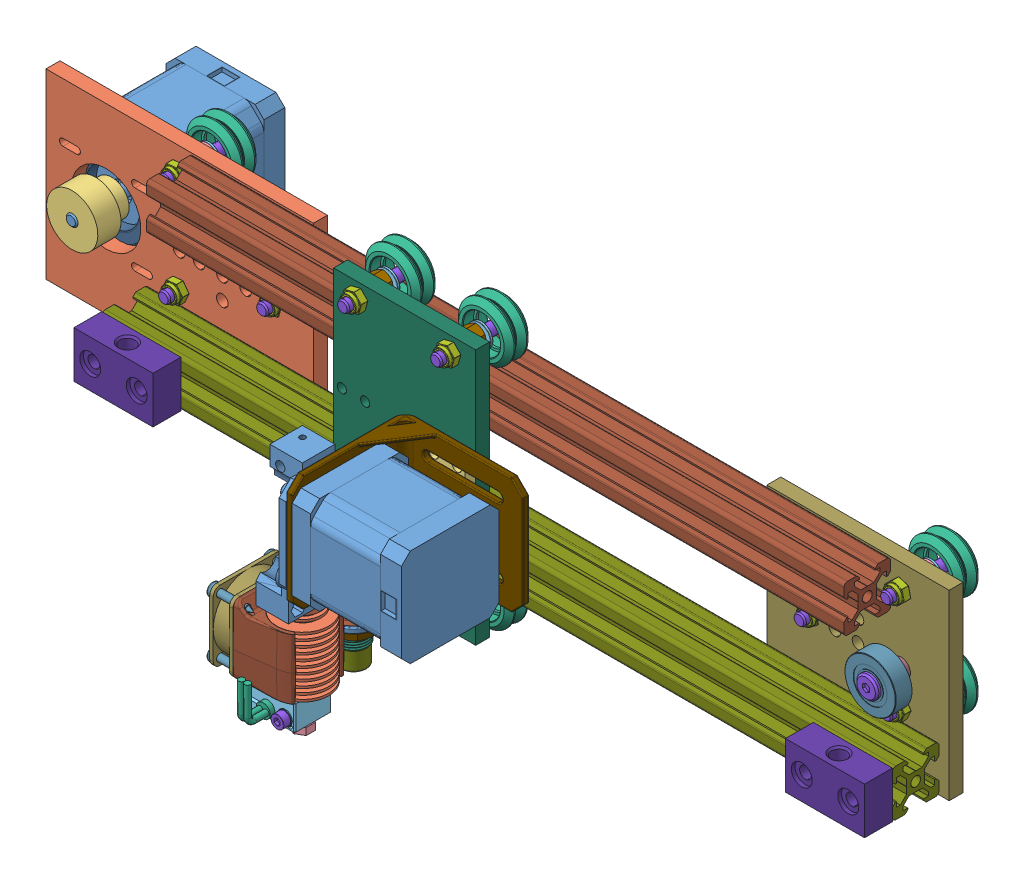
SolidWorks assembly X Axis, configuration Default. Lengths in mm.
107 component instances, 39 part files, 51 mates.
Components (placement in the parent):
- X Motor-1: X Motor [Default] at (-35.3266 39.1515 56.2965) size (149.33 96.33 71)
  - NEMA17_48-1: NEMA17_48 [Default] at (18.5315 36.8987 58.8087) size (42 42 71)
  - X Stepper Mount-1: X Stepper Mount [Default] at (71.5315 36.8987 64.7087) x (1 0 0) z (0 -1 0) size (115 6 78.4)
  - GT2 Pulley-1: GT2 Pulley [Default] at (18.5315 36.8987 72.2337) x (0.991394 0.130915 0) z (-0.130915 0.991394 0) size (22 17 22)
  - Delrin Assembly-1: Delrin Assembly [Default] at (52.9627 66.0979 58.7087) x (0 0 1) z (0.923728 0.383049 0) size (31.75 33.75 33.75)
    - Aluminum Spacer-1: Aluminum Spacer [6mm] at origin size (6 10 10)
    - Precision Shim 10x5x1mm-1: Precision Shim 10x5x1mm [Default] at (-1 0 0) x (1 0 0) z (0 0.993706 0.112022) size (1 10 10)
    - Dual V-Wheel Delrin-1: Dual V-Wheel Delrin [Default] at (-6.115 0 0) x (0 -0.740375 0.672194) z (-1 0 0) size (23.89 23.89 10.23)
    - Nylon Insert Hex Locknut M5-1: Nylon Insert Hex Locknut M5 [Default] at (12 0 0) x (0 -0.231787 0.972767) z (1 0 0) size (7.68 8.82 4.5)
    - 5mm Low Profile Socket Head Screw-1: 5mm Low Profile Socket Head Screw [5mm x 30mm Low Profile Screw] at (-12.98 0 0) x (1 0 0) z (0 0.597414 0.801933) size (31.75 9.5 9.5)
  - Delrin Assembly-2: Delrin Assembly [Default] at (52.9627 22.6994 58.7087) x (0 0 1) z (0.923728 0.383049 0) size (31.75 33.75 33.75)
    - Aluminum Spacer-1: Aluminum Spacer [6mm] at origin size (6 10 10)
    - Precision Shim 10x5x1mm-1: Precision Shim 10x5x1mm [Default] at (-1 0 0) x (1 0 0) z (0 0.993706 0.112022) size (1 10 10)
    - Dual V-Wheel Delrin-1: Dual V-Wheel Delrin [Default] at (-6.115 0 0) x (0 -0.740375 0.672194) z (-1 0 0) size (23.89 23.89 10.23)
    - Nylon Insert Hex Locknut M5-1: Nylon Insert Hex Locknut M5 [Default] at (12 0 0) x (0 -0.231787 0.972767) z (1 0 0) size (7.68 8.82 4.5)
    - 5mm Low Profile Socket Head Screw-1: 5mm Low Profile Socket Head Screw [5mm x 30mm Low Profile Screw] at (-12.98 0 0) x (1 0 0) z (0 0.597414 0.801933) size (31.75 9.5 9.5)
  - Eccentric Delrin Assembly-1: Eccentric Delrin Assembly [Default] at (91.8727 36.8987 61.2087) x (0 0 -1) z (1 0 0) size (31.75 27.59 27.59)
    - Steel Eccentric Spacer-1: Steel Eccentric Spacer [6mm - Mini] at origin size (8.5 9.09 8.71)
    - Precision Shim 10x5x1mm-1: Precision Shim 10x5x1mm [Default] at (6 0 0.79) x (-1 0 0) z (0 0.812589 -0.582837) size (1 10 10)
    - Nylon Insert Hex Locknut M5-1: Nylon Insert Hex Locknut M5 [Default] at (-7 0 0.79) x (0 -0.700969 -0.713192) z (-1 0 0) size (7.68 8.82 4.5)
    - Dual V-Wheel Delrin-1: Dual V-Wheel Delrin [Default] at (11.115 0 0.79) x (0 0.169483 -0.985533) z (1 0 0) size (23.89 23.89 10.23)
    - 5mm Low Profile Socket Head Screw-1: 5mm Low Profile Socket Head Screw [5mm x 30mm Low Profile Screw] at (17.98 0 0.79) x (-1 0 0) z (0 -0.935654 -0.352919) size (31.75 9.5 9.5)
  - Stepper Damper-1: Stepper Damper [Default] at (18.5317 36.8985 58.8087) x (0.707107 0.707107 0) z (0.707107 -0.707107 0) size (51.85 6.11 80.79)
- Upper X Rail-1: Upper X Rail [Default] at (23.5992 105.2494 137.0052) x (0 0 1) z (1 0 0) size (20 20 300)
- X End-1: X End [Default] at (349.9804 66.2549 121.0052) x (-1 0 0) z (0 1 0) size (78.4 6 78.4)
- Delrin Assembly-1: Delrin Assembly [Default] at (328.1737 61.8509 115.0052) x (0 0 1) z (-0.14439 -0.989521 0) size (31.75 33.75 33.75)
  - Aluminum Spacer-1: Aluminum Spacer [6mm] at origin size (6 10 10)
  - Precision Shim 10x5x1mm-1: Precision Shim 10x5x1mm [Default] at (-1 0 0) x (1 0 0) z (0 0.993706 0.112022) size (1 10 10)
  - Dual V-Wheel Delrin-1: Dual V-Wheel Delrin [Default] at (-6.115 0 0) x (0 -0.740375 0.672194) z (-1 0 0) size (23.89 23.89 10.23)
  - Nylon Insert Hex Locknut M5-1: Nylon Insert Hex Locknut M5 [Default] at (12 0 0) x (0 -0.231787 0.972767) z (1 0 0) size (7.68 8.82 4.5)
  - 5mm Low Profile Socket Head Screw-1: 5mm Low Profile Socket Head Screw [5mm x 30mm Low Profile Screw] at (-12.98 0 0) x (1 0 0) z (0 0.597414 0.801933) size (31.75 9.5 9.5)
- Delrin Assembly-2: Delrin Assembly [Default] at (328.1737 105.2494 115.0052) x (0 0 1) z (-1 0 0) size (31.75 33.75 33.75)
  - Aluminum Spacer-1: Aluminum Spacer [6mm] at origin size (6 10 10)
  - Precision Shim 10x5x1mm-1: Precision Shim 10x5x1mm [Default] at (-1 0 0) x (1 0 0) z (0 0.993706 0.112022) size (1 10 10)
  - Dual V-Wheel Delrin-1: Dual V-Wheel Delrin [Default] at (-6.115 0 0) x (0 -0.740375 0.672194) z (-1 0 0) size (23.89 23.89 10.23)
  - Nylon Insert Hex Locknut M5-1: Nylon Insert Hex Locknut M5 [Default] at (12 0 0) x (0 -0.231787 0.972767) z (1 0 0) size (7.68 8.82 4.5)
  - 5mm Low Profile Socket Head Screw-1: 5mm Low Profile Socket Head Screw [5mm x 30mm Low Profile Screw] at (-12.98 0 0) x (1 0 0) z (0 0.597414 0.801933) size (31.75 9.5 9.5)
- Eccentric Delrin Assembly-1: Eccentric Delrin Assembly [Default] at (289.2035 76.3528 117.5052) x (0 0 -1) z (-0.923728 -0.383049 0) size (31.75 27.59 27.59)
  - Steel Eccentric Spacer-1: Steel Eccentric Spacer [6mm - Mini] at origin size (8.5 9.09 8.71)
  - Precision Shim 10x5x1mm-1: Precision Shim 10x5x1mm [Default] at (6 0 0.79) x (-1 0 0) z (0 0.812589 -0.582837) size (1 10 10)
  - Nylon Insert Hex Locknut M5-1: Nylon Insert Hex Locknut M5 [Default] at (-7 0 0.79) x (0 -0.700969 -0.713192) z (-1 0 0) size (7.68 8.82 4.5)
  - Dual V-Wheel Delrin-1: Dual V-Wheel Delrin [Default] at (11.115 0 0.79) x (0 0.169483 -0.985533) z (1 0 0) size (23.89 23.89 10.23)
  - 5mm Low Profile Socket Head Screw-1: 5mm Low Profile Socket Head Screw [5mm x 30mm Low Profile Screw] at (17.98 0 0.79) x (-1 0 0) z (0 -0.935654 -0.352919) size (31.75 9.5 9.5)
- 5mm Low Profile Socket Head Screw-1: 5mm Low Profile Socket Head Screw [5mm x 30mm Low Profile Screw] at (328.1737 76.0502 142.1052) x (0 0 -1) z (1 0 0) size (31.75 9.5 9.5)
- Nylon Spacer-1: Nylon Spacer [.25 inch] at (328.1737 76.0502 133.3552) x (0 0 -1) z (1 0 0) size (6.35 7.94 7.94)
- Ball Bearing 608Z-1: Ball Bearing 608Z [Default] at (328.1737 76.0502 136.8552) x (0 0 -1) z (1 0 0) size (7 22 22)
- Nylon Insert Hex Locknut M5-1: Nylon Insert Hex Locknut M5 [Default] at (328.1737 76.0502 121.0052) x (-0.923728 -0.383049 0) z (0 0 -1) size (7.68 8.82 4.5)
- X Carriage-1: X Carriage [Default] at (142.7674 76.0502 149.1202) x (1 0 0) z (0 -1 0) size (61.08 6 110.03)
- Eccentric Delrin Assembly-2: Eccentric Delrin Assembly [Default] at (161.9774 125.1002 148.1202) x (0 0 -1) z (1 0 0) size (31.75 27.59 27.59)
  - Steel Eccentric Spacer-1: Steel Eccentric Spacer [6mm - Mini] at origin size (8.5 9.09 8.71)
  - Precision Shim 10x5x1mm-1: Precision Shim 10x5x1mm [Default] at (6 0 0.79) x (-1 0 0) z (0 0.812589 -0.582837) size (1 10 10)
  - Nylon Insert Hex Locknut M5-1: Nylon Insert Hex Locknut M5 [Default] at (-7 0 0.79) x (0 -0.700969 -0.713192) z (-1 0 0) size (7.68 8.82 4.5)
  - Dual V-Wheel Delrin-1: Dual V-Wheel Delrin [Default] at (11.115 0 0.79) x (0 0.169483 -0.985533) z (1 0 0) size (23.89 23.89 10.23)
  - 5mm Low Profile Socket Head Screw-1: 5mm Low Profile Socket Head Screw [5mm x 30mm Low Profile Screw] at (17.98 0 0.79) x (-1 0 0) z (0 -0.935654 -0.352919) size (31.75 9.5 9.5)
- Delrin Assembly-3: Delrin Assembly [Default] at (122.7674 27.0002 143.1202) x (0 0 1) z (-1 0 0) size (31.75 33.75 33.75)
  - Aluminum Spacer-1: Aluminum Spacer [6mm] at origin size (6 10 10)
  - Precision Shim 10x5x1mm-1: Precision Shim 10x5x1mm [Default] at (-1 0 0) x (1 0 0) z (0 0.993706 0.112022) size (1 10 10)
  - Dual V-Wheel Delrin-1: Dual V-Wheel Delrin [Default] at (-6.115 0 0) x (0 -0.740375 0.672194) z (-1 0 0) size (23.89 23.89 10.23)
  - Nylon Insert Hex Locknut M5-1: Nylon Insert Hex Locknut M5 [Default] at (12 0 0) x (0 -0.231787 0.972767) z (1 0 0) size (7.68 8.82 4.5)
  - 5mm Low Profile Socket Head Screw-1: 5mm Low Profile Socket Head Screw [5mm x 30mm Low Profile Screw] at (-12.98 0 0) x (1 0 0) z (0 0.597414 0.801933) size (31.75 9.5 9.5)
- Delrin Assembly-4: Delrin Assembly [Default] at (162.7674 27.0002 143.1202) x (0 0 1) z (-1 0 0) size (31.75 33.75 33.75)
  - Aluminum Spacer-1: Aluminum Spacer [6mm] at origin size (6 10 10)
  - Precision Shim 10x5x1mm-1: Precision Shim 10x5x1mm [Default] at (-1 0 0) x (1 0 0) z (0 0.993706 0.112022) size (1 10 10)
  - Dual V-Wheel Delrin-1: Dual V-Wheel Delrin [Default] at (-6.115 0 0) x (0 -0.740375 0.672194) z (-1 0 0) size (23.89 23.89 10.23)
  - Nylon Insert Hex Locknut M5-1: Nylon Insert Hex Locknut M5 [Default] at (12 0 0) x (0 -0.231787 0.972767) z (1 0 0) size (7.68 8.82 4.5)
  - 5mm Low Profile Socket Head Screw-1: 5mm Low Profile Socket Head Screw [5mm x 30mm Low Profile Screw] at (-12.98 0 0) x (1 0 0) z (0 0.597414 0.801933) size (31.75 9.5 9.5)
- Lower X Rail-1: Lower X Rail [Default] at (4.4042 46.8509 137.0052) x (0 0 -1) z (1 0 0) size (20 20 340)
- Nut Block 8mm Acme-1: Nut Block 8mm Acme [Default] at (21.4042 36.8509 153.0052) x (1 0 0) z (0 -1 0) size (34 12 20)
- Nut Block 8mm Acme-2: Nut Block 8mm Acme [Default] at (327.4042 36.8509 153.0052) x (1 0 0) z (0 -1 0) size (34 12 20)
- Eccentric Delrin Assembly-3: Eccentric Delrin Assembly [Default] at (121.9774 125.1002 148.1202) x (0 0 -1) z (1 0 0) size (31.75 27.59 27.59)
  - Steel Eccentric Spacer-1: Steel Eccentric Spacer [6mm - Mini] at origin size (8.5 9.09 8.71)
  - Precision Shim 10x5x1mm-1: Precision Shim 10x5x1mm [Default] at (6 0 0.79) x (-1 0 0) z (0 0.812589 -0.582837) size (1 10 10)
  - Nylon Insert Hex Locknut M5-1: Nylon Insert Hex Locknut M5 [Default] at (-7 0 0.79) x (0 -0.700969 -0.713192) z (-1 0 0) size (7.68 8.82 4.5)
  - Dual V-Wheel Delrin-1: Dual V-Wheel Delrin [Default] at (11.115 0 0.79) x (0 0.169483 -0.985533) z (1 0 0) size (23.89 23.89 10.23)
  - 5mm Low Profile Socket Head Screw-1: 5mm Low Profile Socket Head Screw [5mm x 30mm Low Profile Screw] at (17.98 0 0.79) x (-1 0 0) z (0 -0.935654 -0.352919) size (31.75 9.5 9.5)
- Extruder-1: Extruder [Default] at (209.7945 90.5173 147.8987) x (0 -1 0) z (-1 0 0) size (110.43 53.9 89.7)
  - stepper motor mount-1: stepper motor mount [Default] at (17.4671 41.9715 62.2771) size (50.16 51.25 53.25)
  - NEMA17_48-1: NEMA17_48 [Default] at (17.4671 41.9715 59.6771) size (42 42 71)
  - extruder-2: extruder [Default] at (17.0666 41.9725 62.2771) x (0 1 0) z (0 0 1) size (42 57.13 22.4)
  - E3D All Metal Hotend V6-1: E3D All Metal Hotend V6 [Default] at (80.7686 46.3695 71.7134) x (0 0 -1) z (1 0 0) size (38.16 34.25 62.3)
    - E3D v6 HotEnd - Heatsink-1: E3D v6 HotEnd - Heatsink [Default] at origin size (22.3 22.3 42.7)
    - E3D v6 HotEnd - Heatbreak-1: E3D v6 HotEnd - Heatbreak [Default] at (0 0 7.1) size (7 7 21.9)
    - E3D v6 HotEnd - Nozzle-1: E3D v6 HotEnd - Nozzle [Default] at (0 0 17.6) x (0.866025 0.5 0) z (0 0 1) size (8.08 7 12.5)
    - E3D v6 HotEnd - Heat Block-1: E3D v6 HotEnd - Heat Block [Default] at (-15.5 8 13.6) x (1 0 0) z (0 1 0) size (20 11.5 16)
    - Ceramic Cartridge Heater-1: Ceramic Cartridge Heater [Default] at (-7 10 9.6) x (1 0 0) z (0 1 0) size (6 18 29.25)
    - Thermistor-1: Thermistor [Default] at (2.5 3.65 11.6) x (0.903857 0 0.427835) z (0 -1 0) size (4.52 1.5 4.65)
    - HEXAGON SOCKET HEAD CAP SCREWS_SCB3-4-1: HEXAGON SOCKET HEAD CAP SCREWS_SCB3-4 [Default] at (1 9 8.8) x (0.999538 0 0.030402) z (0 1 0) size (5.5 5.5 7)
    - HEXAGON SOCKET HEAD CAP SCREWS_SCB3-10-1: HEXAGON SOCKET HEAD CAP SCREWS_SCB3-10 [Default] at (-13 0 13.6) size (5.5 5.5 13)
    - Flat Washers_PWF3-1: Flat Washers_PWF3 [Default] at (1 9 8.8) x (1 0 0) z (0 1 0) size (6 6 0.5)
    - E3D-v6 Fan Duct-1: E3D-v6 Fan Duct [Default] x (1 0 0) z (0 1 0) size (22.31 30.04 30)
    - Fan-DC-KDE0503PFB3-Promoco_Fan-DC-KDE0503PFB3-Promoco-1: Fan-DC-KDE0503PFB3-Promoco_Fan-DC-KDE0503PFB3-Promoco [Default] at (-15 0 -15) x (0 0 -1) z (-1 0 0) size (30 30 10)
      - Fan-House-30x30x10-Promoco_Fan-House-KDE0503PFB3-Promoco-1: Fan-House-30x30x10-Promoco_Fan-House-KDE0503PFB3-Promoco [Default] at origin size (30 30 10)
      - Fan-30x30x10-Promoco_Fan-KDE0503PFB3-Promoco-1: Fan-30x30x10-Promoco_Fan-KDE0503PFB3-Promoco [Default] x (0 0 -1) z (-0.999131 0.04169 0) size (8.5 27.91 28)
    - Self Tapping Screws - Pan Head_CSPTRSA-SUS-TP3-16-1: Self Tapping Screws - Pan Head_CSPTRSA-SUS-TP3-16 [Default] at (-25 -12 -27) size (18.01 5.5 5.5)
    - Self Tapping Screws - Pan Head_CSPTRSA-SUS-TP3-16-2: Self Tapping Screws - Pan Head_CSPTRSA-SUS-TP3-16 [Default] at (-25 12 -27) size (18.01 5.5 5.5)
    - Self Tapping Screws - Pan Head_CSPTRSA-SUS-TP3-16-3: Self Tapping Screws - Pan Head_CSPTRSA-SUS-TP3-16 [Default] at (-25 12 -3) size (18.01 5.5 5.5)
    - Self Tapping Screws - Pan Head_CSPTRSA-SUS-TP3-16-4: Self Tapping Screws - Pan Head_CSPTRSA-SUS-TP3-16 [Default] at (-25 -12 -3) size (18.01 5.5 5.5)
- LJ12A3-4-Z-BY-1: LJ12A3-4-Z-BY [Default] at (119.9615 19.2918 175.2983) x (0.585904 0 0.81038) z (0 1 0) size (28.44 28.44 65)
  - LJ12A3-4-Z-BY-1-1: LJ12A3-4-Z-BY-1 [Default] at (0.8756 15.1692 -10.7678) size (12.8 13.04 50.55)
  - LJ12A3-4-Z-BY-2-2: LJ12A3-4-Z-BY-2 [Default] at (0.8756 15.1692 -18.7678) x (1 0 0) z (0 1 0) size (11 10 11)
  - LJ12A3-4-Z-BY-3-1: LJ12A3-4-Z-BY-3 [Default] at (0.8756 15.1692 41.2322) x (1 0 0) z (0 -1 0) size (11 9 11)
  - LJ12A3-4-Z-BY-4-1: LJ12A3-4-Z-BY-4 [Default] at (0.8756 15.1692 -4.7678) x (-0.69421 -0.719772 0) z (0 0 1) size (17 19.63 6)
  - LJ12A3-4-Z-BY-5-1: LJ12A3-4-Z-BY-5 [Default] at (0.8756 15.1692 -0.7678) size (22 22 2.5)
  - LJ12A3-4-Z-BY-5-2: LJ12A3-4-Z-BY-5 [Default] at (0.8756 15.1692 11.7322) x (-0.933046 0.359756 0) z (0 0 1) size (22 22 2.5)
  - LJ12A3-4-Z-BY-4-2: LJ12A3-4-Z-BY-4 [Default] at (0.8756 15.1692 14.2322) x (0.033197 -0.999449 0) z (0 0 1) size (17 19.63 6)
- Probe Mount-1: Probe Mount [Default] at (140.7674 26.024 155.1202) x (1 0 0) z (0 -1 0) size (30 23.6 10)
- Extruder Spacer-1: Extruder Spacer [Default] at (164.7674 73.0502 155.1202) x (1 0 0) z (0 -1 0) size (17 4.5 38)
Mates (geometry in assembly coordinates):
- Coincident1: coincident anti-aligned: plane of X Motor-1/X Stepper Mount-1 through (36.2049 76.0502 127.0052) normal (0 0 1); plane of Upper X Rail-1 through (323.5992 96.7494 127.0052) normal (0 0 -1)
- Coincident4: coincident aligned: plane of X Motor-1/X Stepper Mount-1 through (75.4042 115.2494 127.0052) normal (0 1 0); plane of Upper X Rail-1 through (323.5992 115.2494 128.5052) normal (0 1 0)
- Coincident10: coincident anti-aligned: plane of Upper X Rail-1 through (323.5992 110.1122 127.0052) normal (0 0 -1); plane of X End-1 through (349.9804 66.2549 127.0052) normal (0 0 1)
- Coincident11: coincident aligned: plane of Upper X Rail-1 through (323.5992 115.2494 128.5052) normal (0 1 0); plane of X End-1 through (348.8042 115.2494 127.0052) normal (0 1 0)
- Coincident13: coincident anti-aligned: plane of X End-1 through (349.9804 66.2549 121.0052) normal (0 0 -1); plane of Delrin Assembly-2/Aluminum Spacer-1 through (328.1737 105.2494 121.0052) normal (0 0 1)
- Concentric1: concentric aligned: cylinder of X End-1 through (328.1737 105.2494 127.0052) axis (0 0 -1) radius 2.5; cylinder of Delrin Assembly-2/5mm Low Profile Socket Head Screw-1 through (328.1737 105.2494 102.0252) axis (0 0 -1) radius 2.5
- Concentric2: concentric aligned: cylinder of X End-1 through (328.1737 61.8509 127.0052) axis (0 0 -1) radius 2.5; cylinder of Delrin Assembly-1/5mm Low Profile Socket Head Screw-1 through (328.1737 61.8509 102.0252) axis (0 0 -1) radius 2.5
- Coincident14: coincident anti-aligned: plane of X End-1 through (349.9804 66.2549 121.0052) normal (0 0 -1); plane of Delrin Assembly-1/Aluminum Spacer-1 through (328.1737 61.8509 121.0052) normal (0 0 1)
- Concentric3: concentric aligned: cylinder of X End-1 through (288.4737 76.0502 127.0052) axis (0 0 -1) radius 3.6; cylinder of Eccentric Delrin Assembly-1/5mm Low Profile Socket Head Screw-1 through (288.4737 76.0502 99.5252) axis (0 0 -1) radius 2.5
- Coincident15: coincident anti-aligned: plane of X End-1 through (349.9804 66.2549 121.0052) normal (0 0 -1); plane of Eccentric Delrin Assembly-1/Steel Eccentric Spacer-1 through (289.2035 76.3528 121.0052) normal (0 0 1)
- Coincident16: coincident anti-aligned: plane of X End-1 through (349.9804 66.2549 127.0052) normal (0 0 1); plane of Nylon Spacer-1 through (328.1737 76.0502 127.0052) normal (0 0 -1)
- Concentric4: concentric anti-aligned: cylinder of X End-1 through (328.1737 76.0502 127.0052) axis (0 0 -1) radius 2.5; cylinder of Nylon Spacer-1 through (328.1737 76.0502 127.0052) axis (0 0 1) radius 2.65
- Concentric5: concentric anti-aligned: cylinder of Nylon Spacer-1 through (328.1737 76.0502 127.0052) axis (0 0 1) radius 2.65; cylinder of Ball Bearing 608Z-1 through (328.1737 76.0502 140.3552) axis (0 0 -1) radius 4
- Coincident17: coincident anti-aligned: plane of Nylon Spacer-1 through (328.1737 76.0502 133.3552) normal (0 0 1); plane of Ball Bearing 608Z-1 through (328.1737 76.0502 133.3552) normal (0 0 -1)
- Coincident18: coincident anti-aligned: plane of 5mm Low Profile Socket Head Screw-1 through (328.1737 78.5502 140.3552) normal (0 0 -1); plane of Ball Bearing 608Z-1 through (328.1737 76.0502 140.3552) normal (0 0 1)
- Concentric6: concentric aligned: cylinder of 5mm Low Profile Socket Head Screw-1 through (328.1737 76.0502 142.1052) axis (0 0 1) radius 2.5; cylinder of Nylon Spacer-1 through (328.1737 76.0502 127.0052) axis (0 0 1) radius 2.65
- Coincident19: coincident anti-aligned: plane of X End-1 through (349.9804 66.2549 121.0052) normal (0 0 -1); plane of Nylon Insert Hex Locknut M5-1 through (328.1737 76.0502 121.0052) normal (0 0 1)
- Concentric7: concentric anti-aligned: cylinder of 5mm Low Profile Socket Head Screw-1 through (328.1737 76.0502 142.1052) axis (0 0 1) radius 2.5; cylinder of Nylon Insert Hex Locknut M5-1 through (328.1737 76.0502 121.0052) axis (0 0 -1) radius 2.5
- Distance1: distance = 195.0015 mm anti-aligned: plane of X End-1 through (270.4057 115.2494 127.0052) normal (-1 0 0); plane of X Motor-1/X Stepper Mount-1 through (75.4042 36.8509 127.0052) normal (1 0 0)
- Distance2: distance = 51.805 mm anti-aligned: plane of Upper X Rail-1 through (23.5992 100.3866 146.314) normal (-1 0 0); plane of X Motor-1/X Stepper Mount-1 through (75.4042 36.8509 127.0052) normal (1 0 0)
- Concentric8: concentric aligned: cylinder of X Carriage-1 through (162.7674 125.1002 155.1202) axis (0 0 -1) radius 3.6; cylinder of Eccentric Delrin Assembly-2/5mm Low Profile Socket Head Screw-1 through (162.7674 125.1002 130.1402) axis (0 0 -1) radius 2.5
- Coincident43: coincident anti-aligned: plane of X Carriage-1 through (142.7674 76.0502 155.1202) normal (0 0 1); plane of Eccentric Delrin Assembly-2/Nylon Insert Hex Locknut M5-1 through (162.7674 125.1002 155.1202) normal (0 0 -1)
- Concentric10: concentric aligned: cylinder of X Carriage-1 through (162.7674 27.0002 155.1202) axis (0 0 -1) radius 2.5; cylinder of Delrin Assembly-4/5mm Low Profile Socket Head Screw-1 through (162.7674 27.0002 130.1402) axis (0 0 -1) radius 2.5
- Coincident45: coincident anti-aligned: plane of X Carriage-1 through (142.7674 76.0502 155.1202) normal (0 0 1); plane of Delrin Assembly-4/Nylon Insert Hex Locknut M5-1 through (162.7674 27.0002 155.1202) normal (0 0 -1)
- Concentric11: concentric aligned: cylinder of X Carriage-1 through (122.7674 27.0002 155.1202) axis (0 0 -1) radius 2.5; cylinder of Delrin Assembly-3/5mm Low Profile Socket Head Screw-1 through (122.7674 27.0002 130.1402) axis (0 0 -1) radius 2.5
- Coincident46: coincident anti-aligned: plane of X Carriage-1 through (142.7674 76.0502 155.1202) normal (0 0 1); plane of Delrin Assembly-3/Nylon Insert Hex Locknut M5-1 through (122.7674 27.0002 155.1202) normal (0 0 -1)
- Coincident47: coincident anti-aligned: plane of X Motor-1/X Stepper Mount-1 through (36.2049 76.0502 127.0052) normal (0 0 1); plane of Lower X Rail-1 through (344.4042 41.9882 127.0052) normal (0 0 -1)
- Coincident48: coincident aligned: plane of X Motor-1/X Stepper Mount-1 through (-2.9943 36.8509 127.0052) normal (0 -1 0); plane of Lower X Rail-1 through (344.4042 36.8509 132.1424) normal (0 -1 0)
- Distance3: distance = 71 mm anti-aligned: plane of Lower X Rail-1 through (4.4042 51.7137 127.6963) normal (-1 0 0); plane of X Motor-1/X Stepper Mount-1 through (75.4042 36.8509 127.0052) normal (1 0 0)
- Width2: width aligned: plane of Upper X Rail-1 through (323.5992 115.2494 141.868) normal (0 1 0); plane of Lower X Rail-1 through (344.4042 36.8509 145.5052) normal (0 -1 0); plane of X Carriage-1 through (173.3091 131.0664 155.1202) normal (0 1 0); plane of X Carriage-1 through (112.2256 21.034 155.1202) normal (0 -1 0)
- Coincident50: coincident anti-aligned: plane of Lower X Rail-1 through (344.4042 55.3509 147.0052) normal (0 0 1); plane of Nut Block 8mm Acme-1 through (4.4042 56.8509 147.0052) normal (0 0 -1)
- Coincident51: coincident aligned: plane of Lower X Rail-1 through (344.4042 56.8509 145.5052) normal (0 1 0); plane of Nut Block 8mm Acme-1 through (21.4042 56.8509 153.0052) normal (0 1 0)
- Coincident52: coincident aligned: plane of Lower X Rail-1 through (4.4042 51.7137 127.6963) normal (-1 0 0); plane of Nut Block 8mm Acme-1 through (4.4042 56.8509 159.0052) normal (-1 0 0)
- Coincident53: coincident anti-aligned: plane of Lower X Rail-1 through (344.4042 55.3509 147.0052) normal (0 0 1); plane of Nut Block 8mm Acme-2 through (310.4042 56.8509 147.0052) normal (0 0 -1)
- Coincident54: coincident aligned: plane of Lower X Rail-1 through (344.4042 56.8509 145.5052) normal (0 1 0); plane of Nut Block 8mm Acme-2 through (327.4042 56.8509 153.0052) normal (0 1 0)
- Coincident55: coincident aligned: plane of Lower X Rail-1 through (344.4042 51.7137 127.6963) normal (1 0 0); plane of Nut Block 8mm Acme-2 through (344.4042 56.8509 159.0052) normal (1 0 0)
- Width3: width aligned: plane of Upper X Rail-1 through (323.5992 110.1122 147.0052) normal (0 0 1); plane of Upper X Rail-1 through (323.5992 110.1122 127.0052) normal (0 0 -1); plane of Eccentric Delrin Assembly-2/Dual V-Wheel Delrin-1 through (164.4232 134.7288 142.1202) normal (0 0 1); plane of Eccentric Delrin Assembly-2/Dual V-Wheel Delrin-1 through (164.4232 134.7288 131.8902) normal (0 0 -1)
- Concentric12: concentric aligned: cylinder of X Carriage-1 through (122.7674 125.1002 155.1202) axis (0 0 -1) radius 3.6; cylinder of Eccentric Delrin Assembly-3/5mm Low Profile Socket Head Screw-1 through (122.7674 125.1002 130.1402) axis (0 0 -1) radius 2.5
- Coincident56: coincident anti-aligned: plane of X Carriage-1 through (142.7674 76.0502 155.1202) normal (0 0 1); plane of Eccentric Delrin Assembly-3/Nylon Insert Hex Locknut M5-1 through (122.7674 125.1002 155.1202) normal (0 0 -1)
- Concentric13: concentric anti-aligned: cylinder of X Carriage-1 through (159.7674 88.0502 155.1202) axis (0 0 -1) radius 2; cylinder of Extruder-1/stepper motor mount-1 through (159.7674 88.0502 159.6202) axis (0 0 1) radius 2.1
- Concentric14: concentric aligned: cylinder of X Carriage-1 through (159.7674 58.0502 155.1202) axis (0 0 -1) radius 2; cylinder of Extruder-1/stepper motor mount-1 through (159.7674 58.0502 210.8702) axis (0 0 -1) radius 2.1
- Parallel1: parallel aligned: plane of X Carriage-1 through (173.3091 131.0664 155.1202) normal (0 1 0); plane of LJ12A3-4-Z-BY-1/LJ12A3-4-Z-BY-3-1 through (132.7674 60.524 167.1202) normal (0 1 0)
- Coincident69: coincident anti-aligned: plane of X Carriage-1 through (142.7674 76.0502 155.1202) normal (0 0 1); plane of Probe Mount-1 through (140.7674 26.024 155.1202) normal (0 0 -1)
- Coincident73: coincident anti-aligned: plane of X Carriage-1 through (142.7674 76.0502 155.1202) normal (0 0 1); plane of Extruder Spacer-1 through (164.7674 73.0502 155.1202) normal (0 0 -1)
- Concentric16: concentric aligned: cylinder of X Carriage-1 through (159.7674 88.0502 155.1202) axis (0 0 -1) radius 2; cylinder of Extruder Spacer-1 through (159.7674 88.0502 159.6202) axis (0 0 -1) radius 2
- Concentric17: concentric aligned: cylinder of X Carriage-1 through (169.7674 58.0502 155.1202) axis (0 0 -1) radius 2; cylinder of Extruder Spacer-1 through (169.7674 58.0502 159.6202) axis (0 0 -1) radius 2
- Coincident74: coincident anti-aligned: plane of Extruder-1/stepper motor mount-1 through (147.5174 73.0502 159.6202) normal (0 0 -1); plane of Extruder Spacer-1 through (164.7674 73.0502 159.6202) normal (0 0 1)
- Concentric18: concentric aligned: cylinder of LJ12A3-4-Z-BY-1/LJ12A3-4-Z-BY-1-1 through (132.7674 58.524 167.1202) axis (0 -1 0) radius 6; cylinder of Probe Mount-1 through (132.7674 23.024 167.1202) axis (0 -1 0) radius 6.35
- Coincident75: coincident anti-aligned: plane of LJ12A3-4-Z-BY-1/LJ12A3-4-Z-BY-5-2 through (132.7674 31.024 167.1202) normal (0 -1 0); plane of Probe Mount-1 through (130.7674 31.024 157.1202) normal (0 1 0)
- Concentric21: concentric aligned: cylinder of X Carriage-1 through (145.7674 26.034 155.1202) axis (0 0 -1) radius 1.5; cylinder of Probe Mount-1 through (145.7674 26.034 157.1202) axis (0 0 -1) radius 1.5
- Concentric22: concentric aligned: cylinder of X Carriage-1 through (135.7674 26.034 155.1202) axis (0 0 -1) radius 1.5; cylinder of Probe Mount-1 through (135.7674 26.034 157.1202) axis (0 0 -1) radius 1.5
